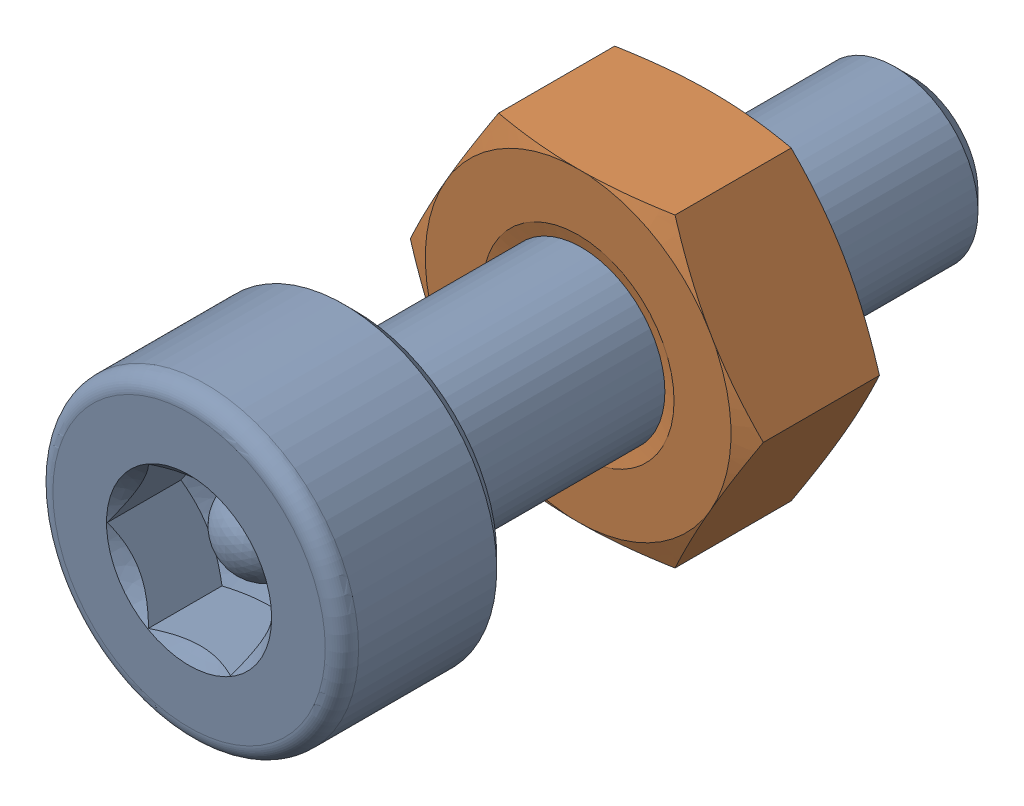
SolidWorks assembly Screw and Nut M3x010_011-1, configuration Varsayılan. Lengths in mm.
Overall size (6.35 5.5 13.14).
2 component instances, 2 part files, 0 mates.
Components (placement in the parent):
- M3x10-Screw010-1-1: M3x10-Screw010-1 [Varsayılan] at origin size (5.5 5.5 13.14)
- M3-Nut042-1-1: M3-Nut042-1 [Varsayılan] at (0 0 -4) x (-1 0 0) z (0 0 -1) size (6.35 5.5 2.4)
